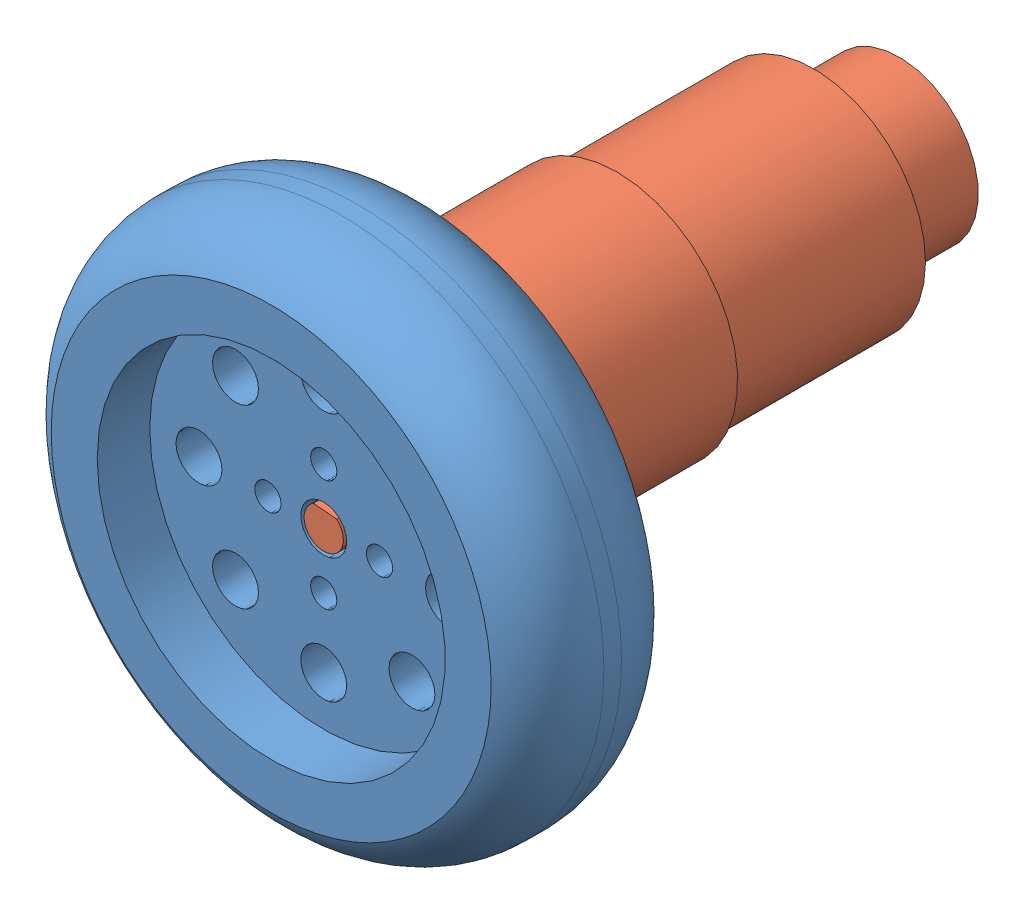
SolidWorks assembly Assemblage1, configuration Défaut. Lengths in mm.
Overall size (80 80 95).
2 component instances, 2 part files, 2 mates.
Components (placement in the parent):
- nouvelles-roues4-1: nouvelles-roues4 [Défaut] at (-18.4651 3.4825 68) size (80 80 24)
- Moteur roues-1: Moteur roues [Défaut] at (-17.8255 10.4532 40) x (0 0 1) z (-0.995816 0.091376 0) size (87 36.8 36.8)
Mates (geometry in assembly coordinates):
- Coaxiale1: concentric: circle of nouvelles-roues4-1; cylinder of Moteur roues-1 through (-18.4651 3.4825 46.2138) axis (0 0 -1) radius 3
- Coïncidente2: coincident aligned: plane of nouvelles-roues4-1 through (-18.4651 3.4825 84) normal (0 0 1); plane of Moteur roues-1 through (-18.191 6.4699 84) normal (0 0 1)
